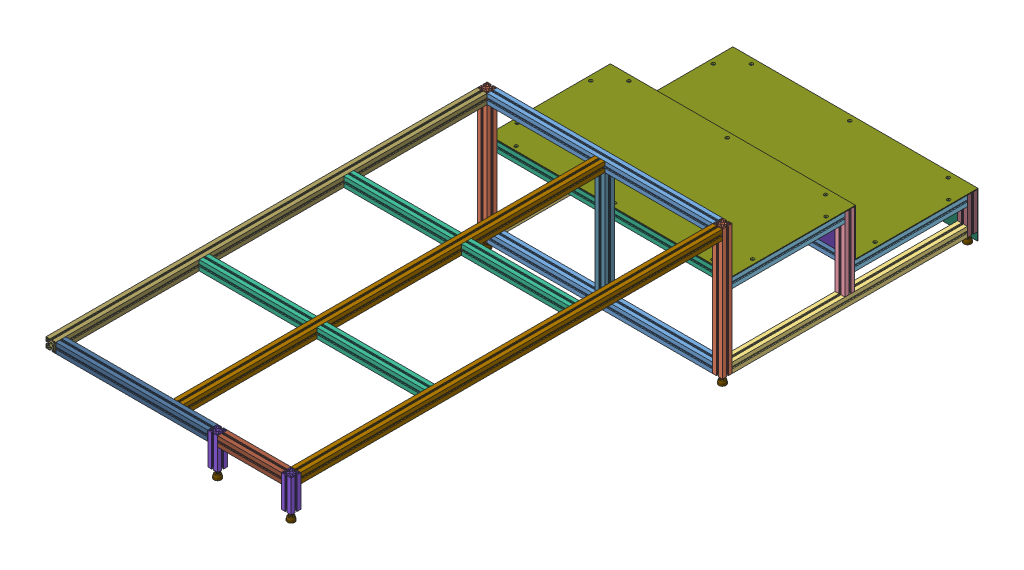
SolidWorks assembly Pd4 00-1-00, configuration Domyślna. Lengths in mm.
Overall size (1000 567 2803).
43 component instances, 18 part files, 0 mates.
Components (placement in the parent):
- Profil 40x40x920-14: Profil 40x40x920 [Default] at (-940 -490 -40) x (0 0 1) z (1 0 0) size (40 40 920)
- Profil 40x40x530-1: Profil 40x40x530 [Default] at (-940 -530 0) x (0 0 -1) z (0 1 0) size (40 40 530)
- Profil 40x40x530-2: Profil 40x40x530 [Default] at (20 -530 0) x (0 0 -1) z (0 1 0) size (40 40 530)
- Profil 40x40x960-1: Profil 40x40x960 [Default] at (-20 -530 -1000) size (40 40 960)
- Profil 40x40x960-2: Profil 40x40x960 [Default] at (-980 -530 -1000) size (40 40 960)
- Profil 40x40x300-1: Profil 40x40x300 [Default] at (-20 -490 -500) x (1 0 0) z (0 1 0) size (40 40 300)
- Profil 40x40x300-2: Profil 40x40x300 [Default] at (-980 -490 -500) x (1 0 0) z (0 1 0) size (40 40 300)
- Profil 40x40x460-9: Profil 40x40x460 [Default] at (-500 -230 -500) size (40 40 460)
- Profil 40x40x440-5: Profil 40x40x440 [Default] at (-20 -230 -80) x (0 0 1) z (-1 0 0) size (40 40 440)
- Profil 40x40x440-6: Profil 40x40x440 [Default] at (-500 -230 -80) x (0 0 1) z (-1 0 0) size (40 40 440)
- Profil 40x40x420-1: Profil 40x40x420 [Default] at (-500 -420 -1000) size (40 40 420)
- Profil 40x40x130-3: Profil 40x40x130 [Default] at (20 -130 1759.796) x (0 0 -1) z (0 1 0) size (40 40 130)
- Profil 40x40x130-4: Profil 40x40x130 [Default] at (-280 -130 1759.796) x (0 0 -1) z (0 1 0) size (40 40 130)
- Profil 40x40x1720-1: Profil 40x40x1720 [Default] at (-20 -40 0) size (40 40 1720)
- Profil 40x40x1720-2: Profil 40x40x1720 [Default] at (-500 -40 0) size (40 40 1720)
- Profil 40x40x620-1: Profil 40x40x620 [Default] at (-940 -40 1760) x (0 0 -1) z (1 0 0) size (40 40 620)
- Profil 40x40x260-1: Profil 40x40x260 [Default] at (-20 -40 1720) x (0 0 1) z (-1 0 0) size (40 40 260)
- Profil 40x40x1760-1: Profil 40x40x1760 [Default] at (-980 -40 0) size (40 40 1760)
- Profil 40x40x150-1: Profil 40x40x150 [Default] at (-980 -380 -1040) x (1 0 0) z (0 -1 0) size (40 40 150)
- Profil 40x40x150-2: Profil 40x40x150 [Default] at (-20 -380 -1040) x (1 0 0) z (0 -1 0) size (40 40 150)
- Profil 40x40x450-2: Profil 40x40x450 [Default] at (-500 -490 0) x (1 0 0) z (0 1 0) size (40 40 450)
- Profil 40x40x440-1: Profil 40x40x440 [Default] at (-20 -40 545) x (0 0 1) z (-1 0 0) size (40 40 440)
- Profil 40x40x440-2: Profil 40x40x440 [Default] at (-20 -40 1135) x (0 0 1) z (-1 0 0) size (40 40 440)
- Profil 40x40x440-3: Profil 40x40x440 [Default] at (-500 -40 1135) x (0 0 1) z (-1 0 0) size (40 40 440)
- Profil 40x40x440-4: Profil 40x40x440 [Default] at (-500 -40 545) x (0 0 1) z (-1 0 0) size (40 40 440)
- Profil 40x40x460-1: Profil 40x40x460 [Default] at (-20 -420 -1000) size (40 40 460)
- Profil 40x40x460-3: Profil 40x40x460 [Default] at (-980 -420 -1000) size (40 40 460)
- Profil 40x40x460-4: Profil 40x40x460 [Default] at (-980 -230 -500) size (40 40 460)
- Profil 40x40x460-5: Profil 40x40x460 [Default] at (-20 -230 -500) size (40 40 460)
- Profil 40x40x920-5: Profil 40x40x920 [Default] at (-940 0 -40) x (0 0 1) z (1 0 0) size (40 40 920)
- Profil 40x40x920-8: Profil 40x40x920 [Default] at (-940 -190 -540) x (0 0 1) z (1 0 0) size (40 40 920)
- Profil 40x40x920-9: Profil 40x40x920 [Default] at (-940 -380 -1040) x (0 0 1) z (1 0 0) size (40 40 920)
- Profil 40x40x920-12: Profil 40x40x920 [Default] at (-940 -380 -580) x (0 0 1) z (1 0 0) size (40 40 920)
- B30(1000x182)-1: B30(1000x182) [Domyślna] at (-480 -471 -1043) size (1000 182 3)
- B28(1000x500)-3: B28(1000x500) [Default] at (-480 -190 -293) x (1 0 0) z (0 1 0) size (1000 500 3)
- B29(1000x190)-2: B29(1000x190) [Default] at (-480 -285 -540) x (-1 0 0) z (0 0 -1) size (1000 190 3)
- B28(1000x500)-4: B28(1000x500) [Default] at (-480 -380 -793) x (1 0 0) z (0 1 0) size (1000 500 3)
- b43-10-3: b43-10 [Domyślna] at (-960 -565 -1020) x (0.92611 0 -0.377253) z (0.377253 0 0.92611) size (29 77 29)
- b43-10-4: b43-10 [Domyślna] at (0 -565 -1020) x (0.341983 0 0.939706) z (-0.939706 0 0.341983) size (29 77 29)
- b43-10-7: b43-10 [Domyślna] at (-300 -169 1739.796) x (0.988522 0 0.15108) z (-0.15108 0 0.988522) size (29 77 29)
- b43-10-8: b43-10 [Domyślna] at (0 -169 1739.796) size (29 77 29)
- b43-10-9: b43-10 [Domyślna] at (-960 -565 -20) x (0.341983 0 0.939706) z (-0.939706 0 0.341983) size (29 77 29)
- b43-10-10: b43-10 [Domyślna] at (0 -565 -20) x (0.341983 0 0.939706) z (-0.939706 0 0.341983) size (29 77 29)
